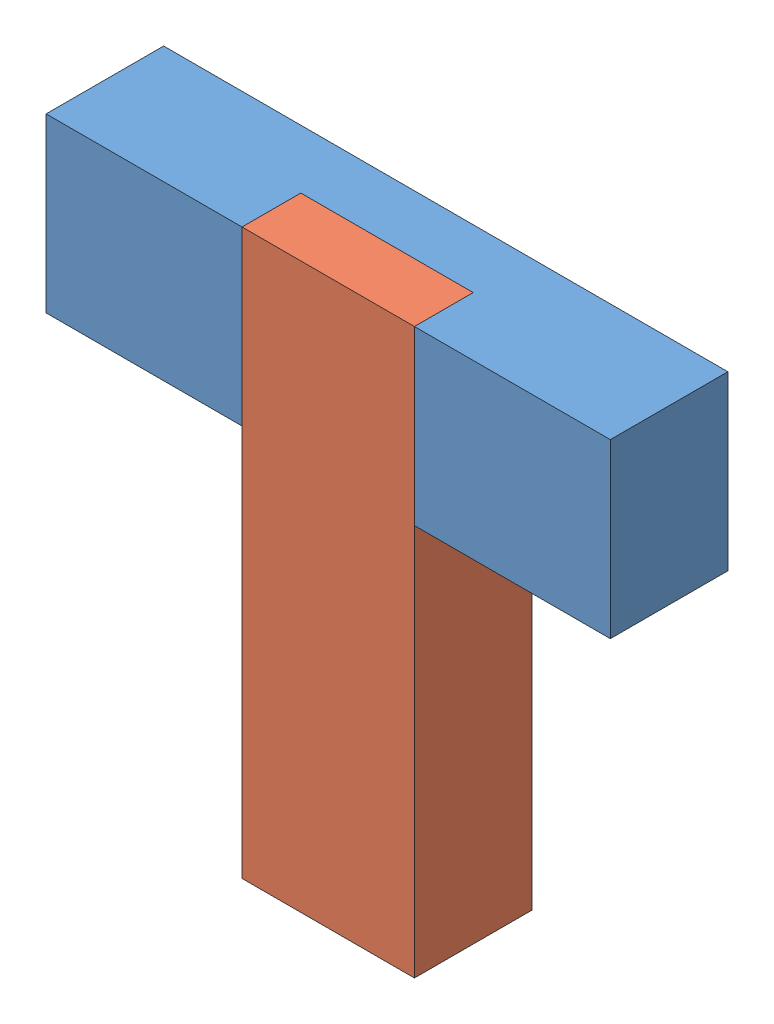
SolidWorks assembly T HAL ASS, configuration Default. Lengths in mm.
Overall size (144 144 30).
2 component instances, 2 part files, 2 mates.
Components (placement in the parent):
- T JOINT 1-1: T JOINT 1 [Default] at (-138.6803 8.0962 17) size (144 44 30)
- T JOINT 2-1: T JOINT 2 [Default] at (-44.6803 -91.9038 17) x (0 0 -1) z (1 0 0) size (30 144 44)
Mates (geometry in assembly coordinates):
- Coincident1: coincident aligned: line of T JOINT 1-1 through (-88.6803 8.0962 2) axis (1 0 0); line of T JOINT 2-1 through (-88.6803 8.0962 2) axis (1 0 0)
- Coincident2: coincident aligned: line of T JOINT 1-1 through (-88.6803 52.0962 2) axis (0 0 1); line of T JOINT 2-1 through (-88.6803 52.0962 2) axis (0 0 1)
